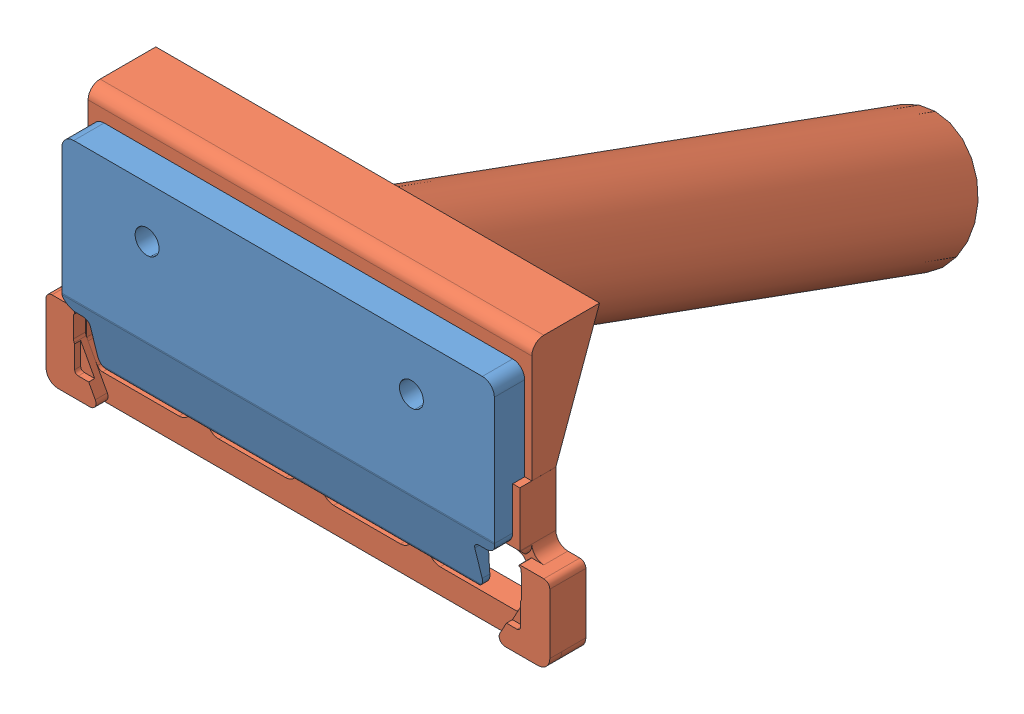
SolidWorks assembly ass1, configuration Default. Lengths in mm.
Overall size (43.2 28.04 54.59).
2 component instances, 2 part files, 3 mates.
Components (placement in the parent):
- for fit assembly-1: for fit assembly [Default] at (0.8749 -4.9081 2.8728) size (36 16.55 14.29)
- for fit 1-1: for fit 1 [Default] at (0.9733 -4.9086 -0.151) x (1 0.000032 0) z (0 0 1) size (43.2 28.04 53.06)
Mates (geometry in assembly coordinates):
- Coincident1: coincident anti-aligned: plane of for fit assembly-1 through (-21.1251 -4.9081 1.849) normal (0 0 -1); plane of for fit 1-1 through (30.947 5.3968 1.849) normal (0 0 1)
- Coincident2: coincident anti-aligned: plane of for fit assembly-1 through (-21.1251 5.3964 2.8728) normal (0 -1 0); plane of for fit 1-1 through (19.4667 5.3964 2.849) normal (0 1 0)
- Tangent1: tangent: circle of for fit assembly-1; curve of for fit 1-1
